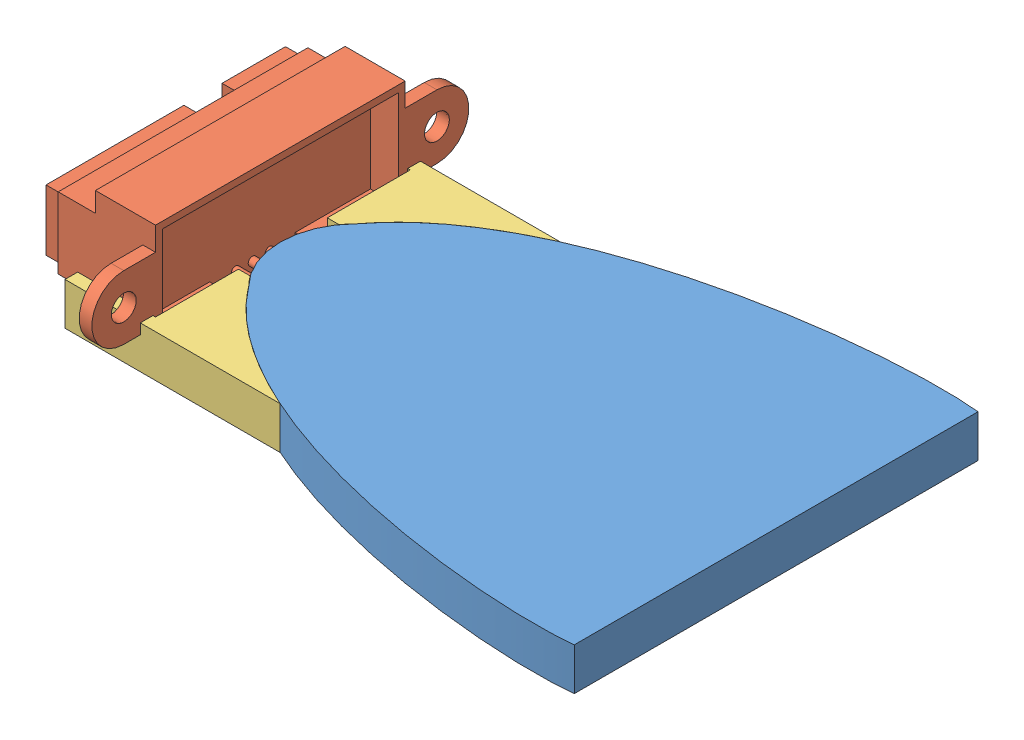
SolidWorks assembly distance-sensor-mount-assembly, configuration Default. Lengths in mm.
Overall size (72.12 18.95 48.88).
3 component instances, 3 part files, 7 mates.
Components (placement in the parent):
- train-nose-profile-1: train-nose-profile [Default] at origin size (58.58 5 48.88)
- sharp-distance-sensor-1: sharp-distance-sensor [Default] at (-55.9 7.55 0) x (0 0 1) z (0 -1 0) size (44.55 15.24 18.95)
- distance-sensor-holder-1: distance-sensor-holder [Default] x (-1 0 0) z (0 -1 0) size (25.42 33.1 5)
Mates (geometry in assembly coordinates):
- Distance1: distance = 1 mm aligned: plane of sharp-distance-sensor-1 through (-57.4 1 0) normal (0 -1 0); plane of train-nose-profile-1 through (0 0 0) normal (0 -1 0)
- Coincident2: coincident aligned: plane of train-nose-profile-1 through (0 0 0) normal (0 0 1); plane of sharp-distance-sensor-1
- Tangent1: tangent anti-aligned: cylinder of train-nose-profile-1 through (-46.9 5 0) axis (0 -1 0) radius 9; plane of sharp-distance-sensor-1 through (-55.9 7.55 0) normal (1 0 0)
- InPlace1: in place: plane of train-nose-profile-1 through (0 0 0) normal (0 -1 0); plane of distance-sensor-holder-1 through (0 0 0) normal (0 -1 0); moOrthogonalPlaneRef_w of train-nose-profile-1 through (0 0 0) normal (0 -1 0); unknown of distance-sensor-holder-1; plane of train-nose-profile-1 through (0 0 0) normal (0 -1 0); line of distance-sensor-holder-1 through (55 -55 0) axis (0 0 -1); plane of train-nose-profile-1 through (0 0 0) normal (0 -1 0); unknown of distance-sensor-holder-1
- Coincident3: coincident aligned: plane of train-nose-profile-1; plane of distance-sensor-holder-1
- Coincident4: coincident aligned: moOrthogonalPlaneRef_w of train-nose-profile-1 through (0 0 0) normal (0 0 -1); plane of distance-sensor-holder-1
- Coincident5: coincident anti-aligned: moOrthogonalPlaneRef_w of train-nose-profile-1 through (0 0 0) normal (1 0 0); plane of distance-sensor-holder-1
